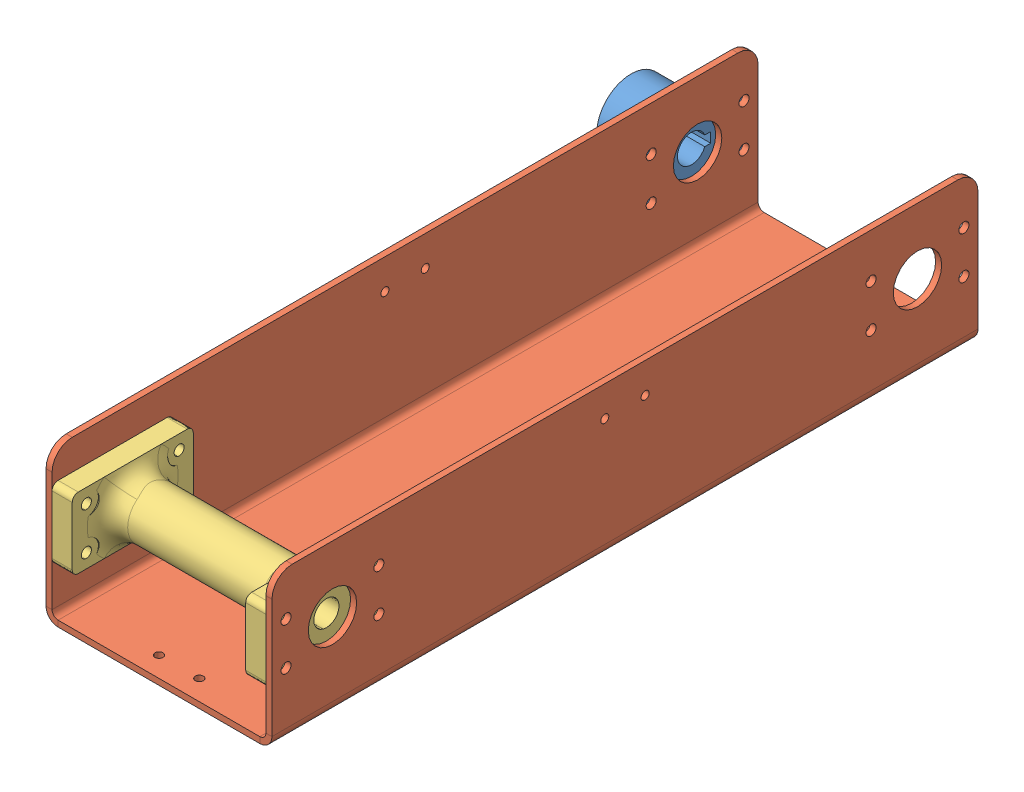
SolidWorks assembly Arm rest sheet metal, configuration Default. Lengths in mm.
Overall size (142 75 350).
3 component instances, 3 part files, 8 mates.
Components (placement in the parent):
- Shaft arm CNC-1: Shaft arm CNC [Default] at origin size (30 35 60)
- 1xArm rester sheet metal-1: 1xArm rester sheet metal [Default] at (86 -39.5 320) x (0 0 1) z (-1 0 0) size (350 75 112)
- handle-1: handle [Default] at (139 -39.5 320) x (0 0 1) z (-1 0 0) size (60 35 106)
Mates (geometry in assembly coordinates):
- Coincident1: coordinate: point of Shaft arm CNC-1
- Coincident2: coincident anti-aligned: plane of Shaft arm CNC-1 through (30 0 0) normal (1 0 0); plane of 1xArm rester sheet metal-1 through (30 -39.5 320) normal (-1 0 0)
- Coincident3: coincident aligned: plane of Shaft arm CNC-1 through (30 -17.5 -30) normal (0 0 -1); plane of 1xArm rester sheet metal-1 through (30 -39.5 -30) normal (0 0 -1)
- Distance1: distance = 15 mm aligned: plane of Shaft arm CNC-1 through (30 17.5 -30) normal (0 1 0); plane of 1xArm rester sheet metal-1 through (30 32.5 -30) normal (0 1 0)
- InPlace1: in place: plane of 1xArm rester sheet metal-1 through (139 -39.5 320) normal (-1 0 0); plane of ? through (139 0 0) normal (-1 0 0); moOrthogonalPlaneRef_w of 1xArm rester sheet metal-1 through (139 -39.5 320) normal (-1 0 0); plane of ? through (139 0 0) normal (0 1 0); plane of 1xArm rester sheet metal-1 through (139 -39.5 320) normal (-1 0 0); plane of ? through (139 0 0) normal (0 0 1); plane of 1xArm rester sheet metal-1 through (139 -39.5 320) normal (-1 0 0); unknown of handle-1
- Coincident4: coincident aligned: plane of ?; plane of ?
- Coincident5: coincident aligned: moOrthogonalPlaneRef_w of 1xArm rester sheet metal-1 through (139 -39.5 320) normal (0 1 0); plane of Part2^Arm rest sheet metal-1 through (139 -39.5 320) normal (0 1 0)
- Coincident6: coincident anti-aligned: moOrthogonalPlaneRef_w of 1xArm rester sheet metal-1 through (139 -39.5 320) normal (0 0 -1); plane of Part2^Arm rest sheet metal-1 through (139 -39.5 320) normal (0 0 1)
